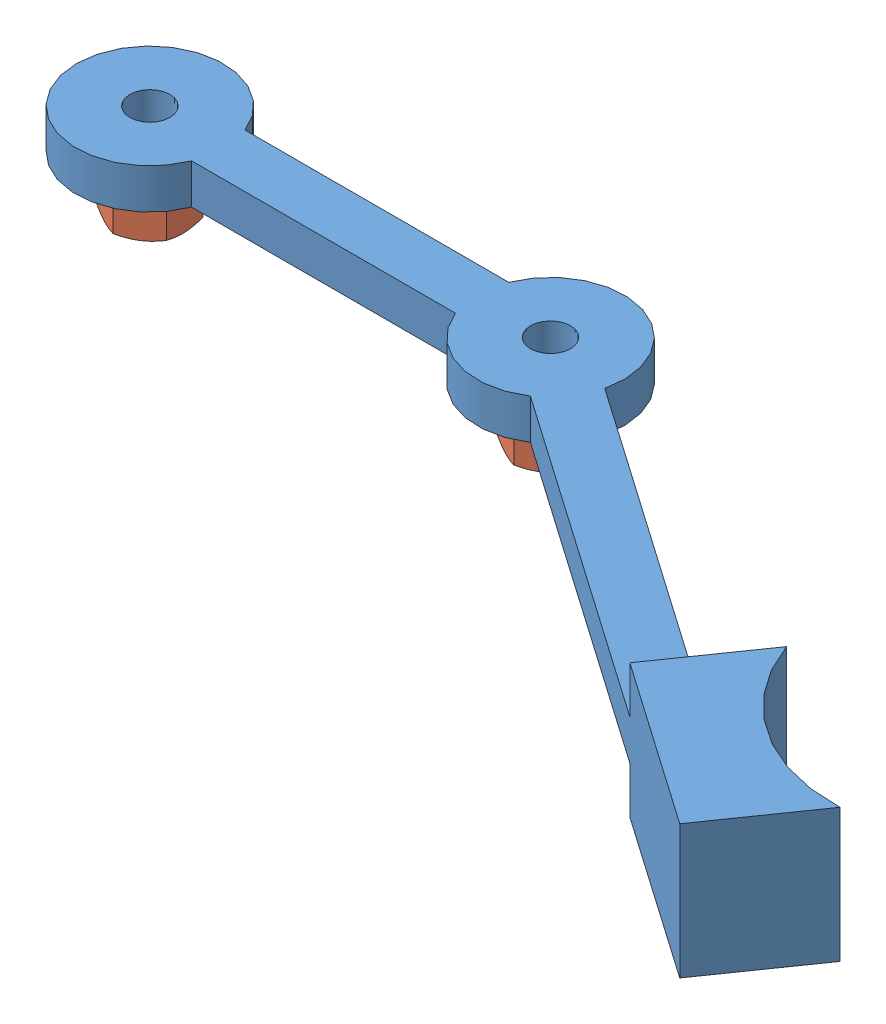
SolidWorks assembly Assem7.6, configuration Default. Lengths in mm.
Overall size (80.31 10.5 35.71).
5 component instances, 3 part files, 12 mates.
Components (placement in the parent):
- Part17-1: Part17 [Default] at origin size (80.31 10 35.71)
- navrtka8-1: navrtka8 [Default] at (30 -4 0) x (1 0 0) z (0 1 0) size (5.57 5.77 3)
- navrtka8-2: navrtka8 [Default] at (0 -4 0) x (1 0 0) z (0 1 0) size (5.57 5.77 3)
- sajbna9-1: sajbna9 [Default] at (0 -2.5 0) size (8 1 8)
- sajbna9-2: sajbna9 [Default] at (30 -2.5 0) size (8 1 8)
Mates (geometry in assembly coordinates):
- Concentric1: concentric anti-aligned: cylinder of Part17-1 through (0 -1.5 0) axis (0 1 0) radius 1.5; cylinder of sajbna9-1 through (0 -1.5 0) axis (0 -1 0) radius 1.5
- Coincident1: coincident anti-aligned: plane of Part17-1 through (0 -1.5 0) normal (0 -1 0); plane of sajbna9-1 through (0 -1.5 0) normal (0 1 0)
- Concentric2: concentric anti-aligned: cylinder of Part17-1 through (30 -1.5 0) axis (0 1 0) radius 1.5; cylinder of sajbna9-2 through (30 -1.5 0) axis (0 -1 0) radius 1.5
- Coincident2: coincident anti-aligned: plane of Part17-1 through (0 -1.5 0) normal (0 -1 0); plane of sajbna9-2 through (30 -1.5 0) normal (0 1 0)
- Concentric3: concentric anti-aligned: cylinder of Part17-1 through (0 -1.5 0) axis (0 1 0) radius 1.5; circle of navrtka8-2
- Coincident3: coincident anti-aligned: plane of navrtka8-2 through (0 -2.5 0) normal (0 1 0); plane of sajbna9-1 through (0 -2.5 0) normal (0 -1 0)
- Concentric4: concentric anti-aligned: cylinder of Part17-1 through (30 -1.5 0) axis (0 1 0) radius 1.5; circle of navrtka8-1
- Coincident4: coincident anti-aligned: plane of navrtka8-1 through (30 -2.5 0) normal (0 1 0); plane of sajbna9-2 through (30 -2.5 0) normal (0 -1 0)
- Parallel1: parallel anti-aligned: plane of navrtka8-1 through (30 -4 0) normal (0 0 -1); plane of assembly
- Parallel2: parallel anti-aligned: plane of navrtka8-2 through (0 -4 0) normal (0 0 -1); plane of assembly
- Parallel3: parallel aligned: plane of sajbna9-1 through (0 -2.5 0) normal (0 0 1); plane of assembly
- Coincident8: coincident aligned: plane of sajbna9-2 through (30 -2.5 0) normal (0 0 1); plane of assembly
